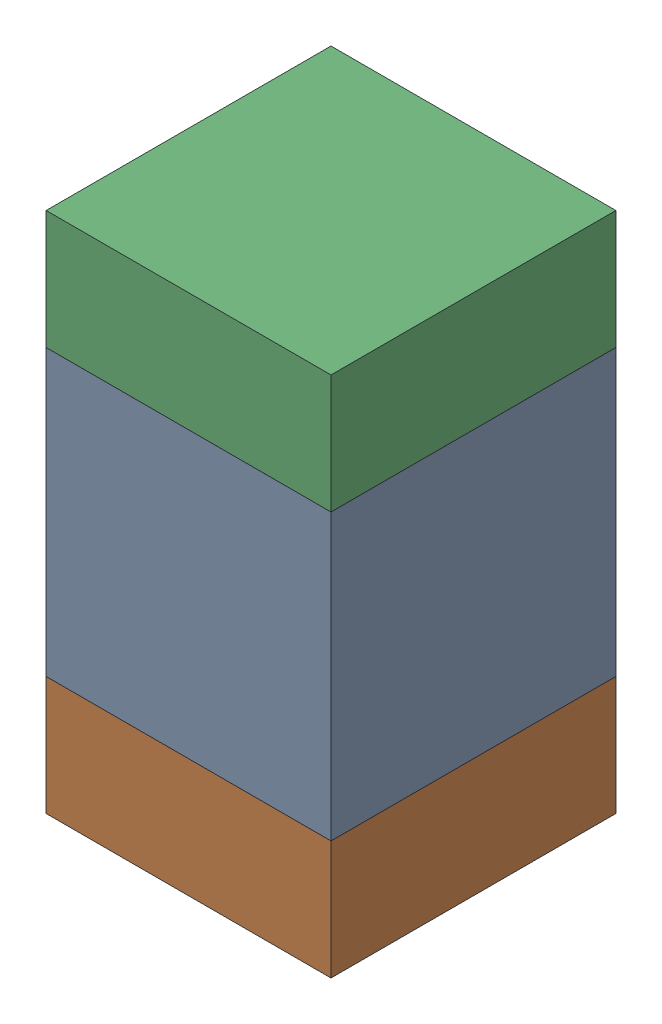
SolidWorks assembly C108_2PCB, configuration Default. Lengths in mm.
Overall size (0.6 1.1 0.6).
6 component instances, 2 part files, 0 mates.
Components (placement in the parent):
- 761606048-1: 761606048 [Default] at (116.7 87.9 0) size (0.6 0.6 0.6)
  - Extruded_9-1: Extruded_9 [Default] at origin size (0.6 0.6 0.6)
- 854785296-1: 854785296 [Default] at (116.7 87.475 0) size (0.6 0.25 0.6)
  - Extruded_10-1: Extruded_10 [Default] at origin size (0.6 0.25 0.6)
- 854785296-2: 854785296 [Default] at (116.7 88.325 0) size (0.6 0.25 0.6)
  - Extruded_10-1: Extruded_10 [Default] at origin size (0.6 0.25 0.6)
